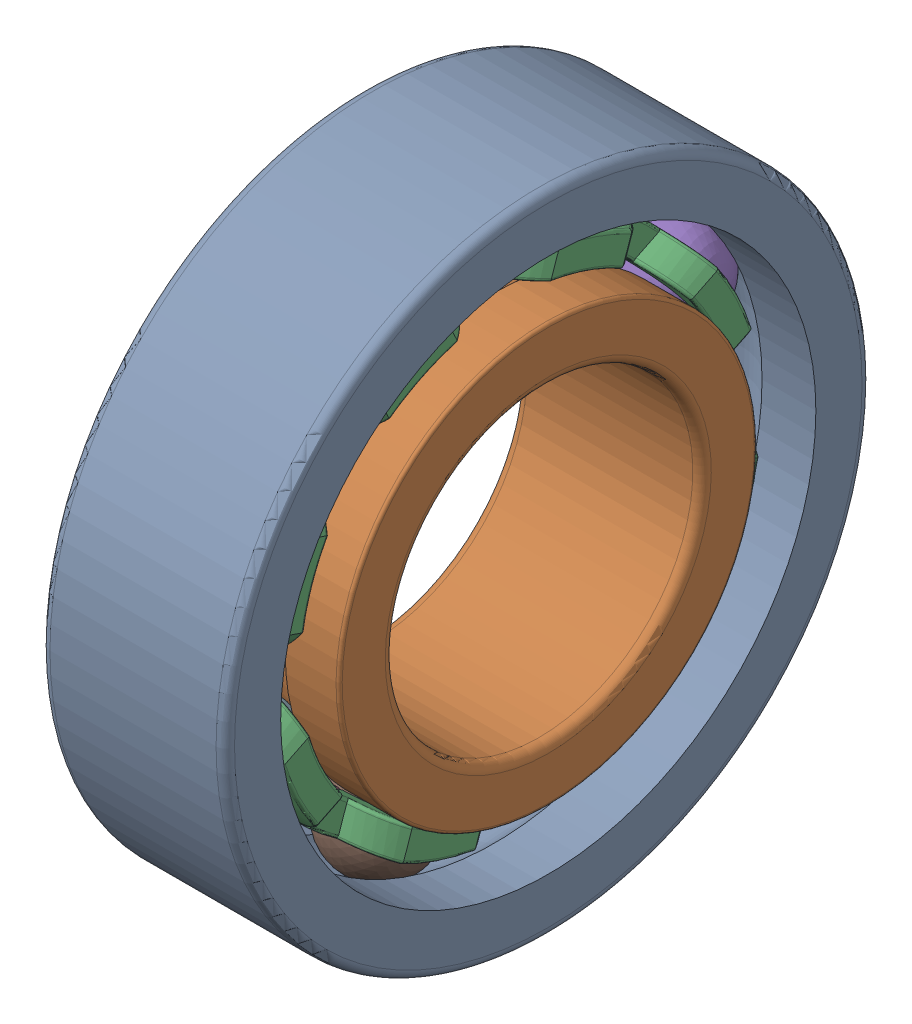
SolidWorks assembly Ballbearing assembly, configuration Default. Lengths in mm.
Overall size (12 42.81 42.81).
12 component instances, 4 part files, 27 mates.
Components (placement in the parent):
- Outer race-1: Outer race [Default] at (620.3041 884.6505 1286.8797) size (12 42 42)
- Inner race-1: Inner race [Default] at (620.3041 872.7169 1293.6294) x (0 -0.999952 0.009829) z (-1 0 0) size (27.2 27.2 12)
- Cage-1: Cage [Default] at (624.3041 887.7851 1281.6889) x (0 -0.324429 -0.94591) z (0 0.94591 -0.324429) size (32 4.21 32)
- Cage-2: Cage [Default] at (616.3041 887.0228 1293.911) x (0 -0.439453 0.898265) z (0 0.898265 0.439453) size (32 4.21 32)
- Balls-1: Balls [Default] at (620.3041 879.4192 1273.0442) x (0.984798 0.104575 -0.138697) z (0.136539 0.027557 0.990251) size (6.4 6.4 6.4)
- Balls-4: Balls [Default] at (620.3041 867.6535 1272.3103) x (0.912784 0.28998 -0.28764) z (0.325157 -0.089717 0.941394) size (6.4 6.4 6.4)
- Balls-5: Balls [Default] at (620.3041 887.2199 1281.8827) x (0.789371 0.442365 -0.425683) z (0.529644 -0.140091 0.836572) size (6.4 6.4 6.4)
- Balls-6: Balls [Default] at (620.3041 886.486 1293.6484) x (0.226476 0.714042 -0.66246) z (0.900591 0.105551 0.421657) size (6.4 6.4 6.4)
- Balls-9: Balls [Default] at (620.3041 858.815 1280.111) x (0.787167 0.479497 -0.38788) z (0.51496 -0.164909 0.841202) size (6.4 6.4 6.4)
- Balls-10: Balls [Default] at (620.3041 877.6475 1301.4491) x (-0.012799 0.828595 -0.559703) z (0.942246 0.197345 0.270606) size (6.4 6.4 6.4)
- Balls-11: Balls [Default] at (620.3041 858.0811 1291.8767) size (6.4 6.4 6.4)
- Balls-12: Balls [Default] at (620.3041 865.8818 1300.7153) size (6.4 6.4 6.4)
Mates (geometry in assembly coordinates):
- Concentric1: concentric anti-aligned: cylinder of Outer race-1 through (626.3041 872.6505 1286.8797) axis (1 0 0) radius 17.4; cylinder of Inner race-1 through (614.3041 872.6505 1286.8797) axis (-1 0 0) radius 13.6
- Coincident1: coincident aligned: plane of Outer race-1 through (626.3041 884.6505 1286.8797) normal (1 0 0); plane of Inner race-1 through (626.3041 872.7169 1293.6294) normal (1 0 0)
- Coincident2: coincident anti-aligned: plane of Cage-1 through (620.3041 872.6505 1286.8797) normal (-1 0 0); plane of Cage-2 through (620.3041 872.6505 1286.8797) normal (1 0 0)
- Concentric2: concentric aligned: circle of Cage-1; circle of Cage-2
- Coincident4: coincident anti-aligned: line of Cage-1 through (620.3041 875.8558 1273.0462) axis (0 0.439453 -0.898265); line of Cage-2 through (620.3041 876.5568 1271.6134) axis (0 -0.439453 0.898265)
- Concentric3: concentric anti-aligned: circle of Inner race-1; circle of Cage-1
- Tangent1: tangent anti-aligned: torus of Outer race-1; sphere of Balls-1
- Concentric4: concentric: cylinder of Cage-1 through (620.3041 882.5942 1266.5543) axis (0 -0.439453 0.898265) radius 3.2; sphere of Balls-1
- Tangent3: tangent anti-aligned: torus of Outer race-1; sphere of Balls-4
- Concentric5: concentric: cylinder of Cage-2 through (620.3041 879.9915 1308.2832) axis (0 -0.324429 -0.94591) radius 3.2; sphere of Balls-4
- Tangent4: tangent anti-aligned: torus of Outer race-1; sphere of Balls-5
- Concentric6: concentric: cylinder of Cage-2 through (620.3041 851.247 1294.2207) axis (0 0.94591 -0.324429) radius 3.2; sphere of Balls-5
- Tangent5: tangent anti-aligned: torus of Outer race-1; sphere of Balls-6
- Concentric7: concentric: cylinder of Cage-2 through (620.3041 887.0228 1293.911) axis (0 -0.898265 -0.439453) radius 3.2; sphere of Balls-6
- Tangent6: tangent anti-aligned: torus of Outer race-1; sphere of Balls-7
- Concentric10: concentric: cylinder of Cage-2 through (620.3041 887.0228 1293.911) axis (0 -0.898265 -0.439453) radius 3.2; sphere of Balls-7
- Tangent7: tangent anti-aligned: torus of Outer race-1; sphere of Balls-8
- Concentric9: concentric: cylinder of Cage-2 through (620.3041 851.247 1294.2207) axis (0 0.94591 -0.324429) radius 3.2; sphere of Balls-8
- Tangent9: tangent anti-aligned: torus of Outer race-1; sphere of Balls-9
- Concentric11: concentric: cylinder of Cage-2 through (620.3041 887.0228 1293.911) axis (0 -0.898265 -0.439453) radius 3.2; sphere of Balls-9
- Tangent10: tangent anti-aligned: torus of Outer race-1; sphere of Balls-10
- Concentric12: concentric: cylinder of Cage-2 through (620.3041 879.9915 1308.2832) axis (0 -0.324429 -0.94591) radius 3.2; sphere of Balls-10
- Tangent11: tangent anti-aligned: torus of Outer race-1; sphere of Balls-11
- Concentric13: concentric: cylinder of Cage-2 through (620.3041 851.247 1294.2207) axis (0 0.94591 -0.324429) radius 3.2; sphere of Balls-11
- Tangent13: tangent anti-aligned: torus of Outer race-1; sphere of Balls-12
- Concentric14: concentric: cylinder of Cage-2 through (620.3041 865.6193 1301.252) axis (0 0.439453 -0.898265) radius 3.2; sphere of Balls-12
- GearMate1: gear = 31.6 : 26.8 mm: circle of Inner race-1; circle of Cage-1
